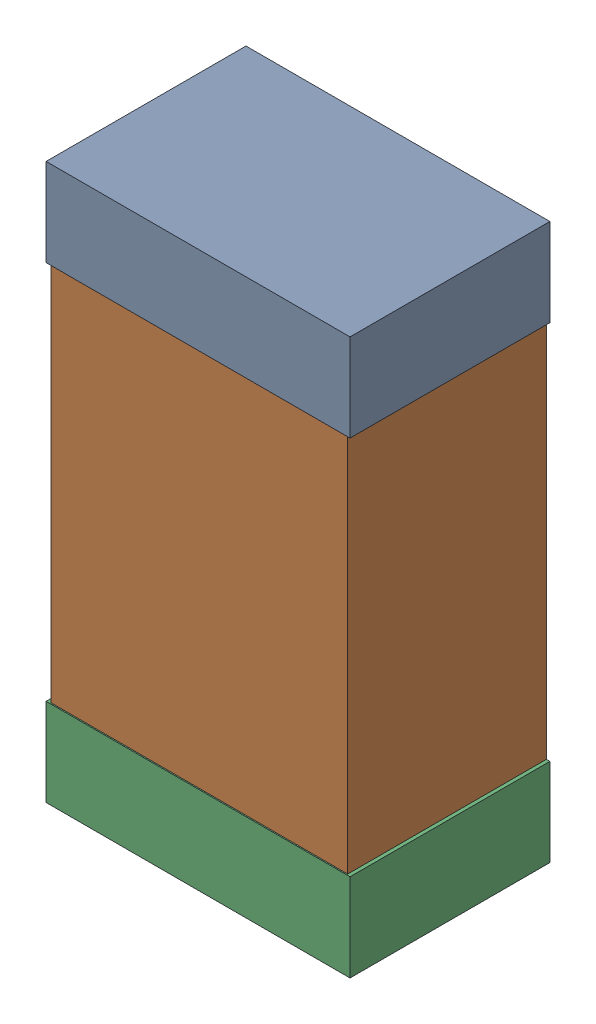
SolidWorks assembly Kanaloa_v2.0.0_Power_7, configuration Default. Lengths in mm.
Overall size (1.3 2.38 0.85).
6 component instances, 2 part files, 0 mates.
Components (placement in the parent):
- 330415056-1: 330415056 [Default] at (129.2818 82.1994 0) size (1.3 0.38 0.85)
  - Extruded_2-1: Extruded_2 [Default] at origin size (1.3 0.38 0.85)
- 334787376-1: 334787376 [Default] at (129.2818 81.1994 0) size (1.27 2.2 0.85)
  - Extruded_16-1: Extruded_16 [Default] at origin size (1.27 2.2 0.85)
- 330415056-2: 330415056 [Default] at (129.2818 80.1994 0) size (1.3 0.38 0.85)
  - Extruded_2-1: Extruded_2 [Default] at origin size (1.3 0.38 0.85)
